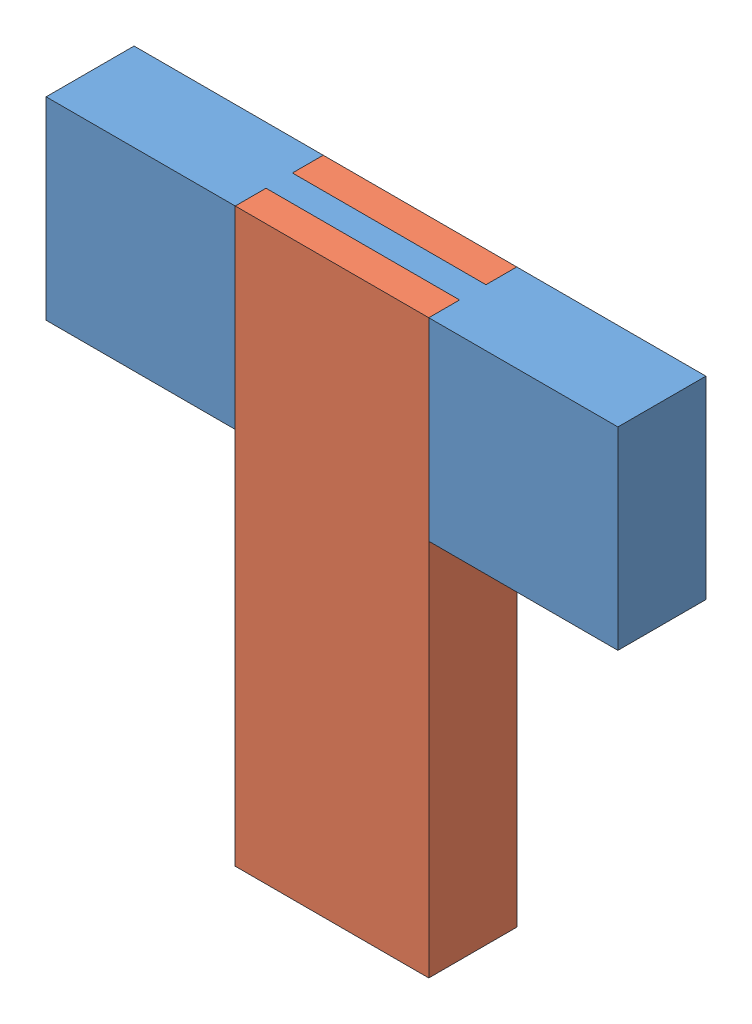
SolidWorks assembly BRIDLE JOINT, configuration Default. Lengths in mm.
Overall size (130 130 20).
2 component instances, 2 part files, 3 mates.
Components (placement in the parent):
- PART1-1: PART1 [Default] at origin size (130 44 20)
- PART2-1: PART2 [Default] at (43 -130 0) x (0 1 0) z (-1 0 0) size (130 20 44)
Mates (geometry in assembly coordinates):
- Coincident2: coincident anti-aligned: plane of PART1-1 through (87 -44 -13) normal (-1 0 0); plane of PART2-1 through (87 -130 -20) normal (1 0 0)
- Coincident3: coincident aligned: plane of PART1-1 through (0 0 -20) normal (0 1 0); plane of PART2-1 through (43 0 -20) normal (0 1 0)
- Coincident4: coincident anti-aligned: line of PART1-1 through (43 0 -13) axis (1 0 0); line of PART2-1 through (87 0 -13) axis (-1 0 0)
